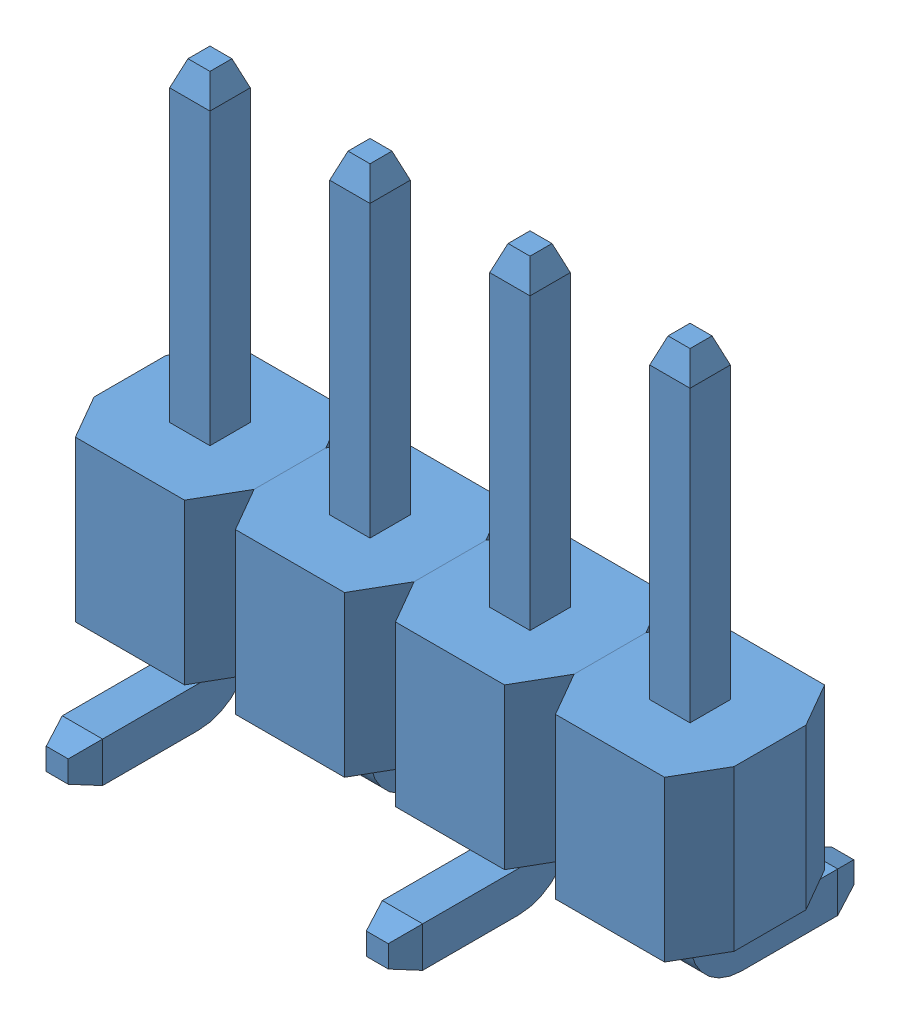
SolidWorks assembly HEADER, PIN, MALE, SMD, 2.54mm Pitch, configuration 4. Lengths in mm.
Overall size (10.16 8.82 4.85).
4 component instances, 1 part files, 3 mates.
Components (placement in the parent):
- header SMD 2,54mm-1: header SMD 2,54mm [Default] at (-1.3017 1.793 -0.5313)
- header SMD 2,54mm-2: header SMD 2,54mm [Default] at (-3.8417 1.793 4.3173) x (-1 0 0) z (0 0 -1)
- header SMD 2,54mm-3: header SMD 2,54mm [Default] at (1.2383 1.793 4.3173) x (-1 0 0) z (0 0 -1)
- header SMD 2,54mm-4: header SMD 2,54mm [Default] at (3.7783 1.793 -0.5313)
Mates (geometry in assembly coordinates):
- Coincident2: coincident aligned: plane of header SMD 2,54mm-1 through (-2.5717 -0.0665 3.163) normal (0 1 0); plane of header SMD 2,54mm-2 through (-2.5717 -0.0665 0.623) normal (0 1 0)
- Coincident3: coincident aligned: plane of header SMD 2,54mm-1 through (-0.0317 -0.0665 3.163) normal (0 0 1); plane of header SMD 2,54mm-2 through (-5.1117 -0.0665 3.163) normal (0 0 1)
- Coincident7: coincident anti-aligned: plane of header SMD 2,54mm-1 through (-2.5717 -0.0665 0.623) normal (-1 0 0); plane of header SMD 2,54mm-2 through (-2.5717 -0.0665 3.163) normal (1 0 0)
